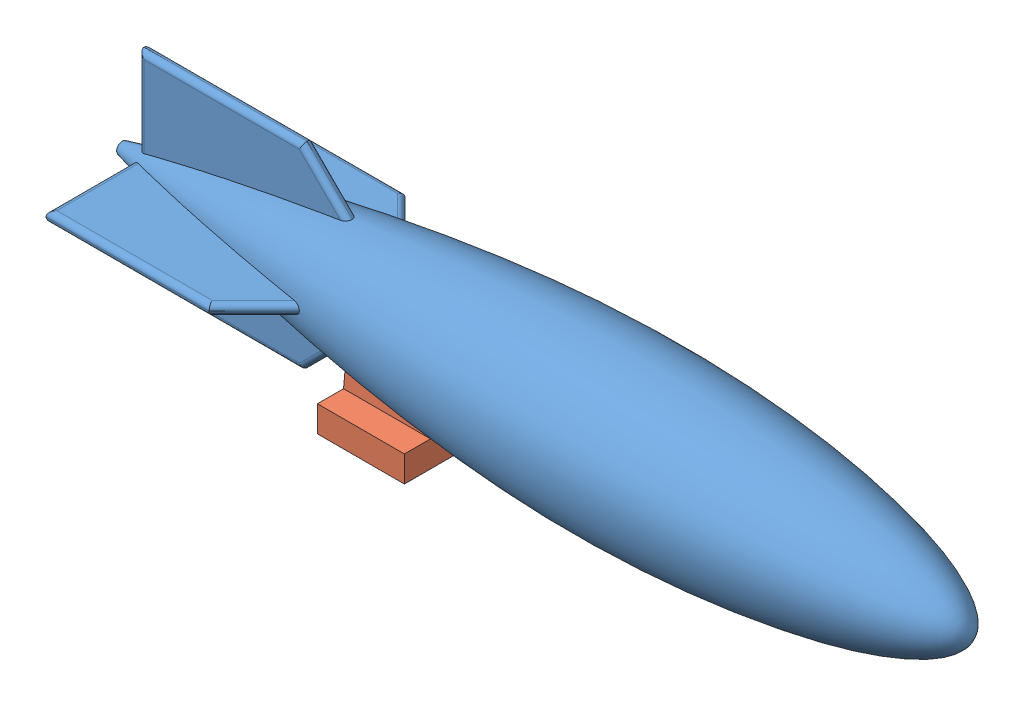
SolidWorks assembly Toypedo plus rail, configuration Default. Lengths in mm.
Overall size (123.83 34.75 34.75).
2 component instances, 2 part files, 4 mates.
Components (placement in the parent):
- Toypedo-1: Toypedo [Default] at origin size (123.83 34.75 34.75)
- Trigger Lock-1: Trigger Lock [Default] at (-90.2483 -16.8575 0.002) size (12.7 16.51 10.16)
Mates (geometry in assembly coordinates):
- Parallel1: parallel aligned: line of Toypedo-1 through (-96.8375 -14.3175 0) axis (-1 0 0); line of Trigger Lock-1 through (-77.5483 -0.3475 0.002) axis (-1 0 0)
- Coincident6: coincident: point of Toypedo-1; plane of Trigger Lock-1 through (-90.2483 -13.0475 1.272) normal (-1 0 0)
- Distance1: distance = 1.27 mm: line of Toypedo-1 through (-96.8375 -14.3175 0) axis (-1 0 0); plane of Trigger Lock-1 through (-77.5483 -13.0475 1.272) normal (0 1 0)
- Parallel3: parallel aligned: plane of Toypedo-1 through (-120.65 -0.7937 -14.3175) normal (0 -1 0); plane of Trigger Lock-1 through (-77.5483 -16.8575 -5.078) normal (0 -1 0)
